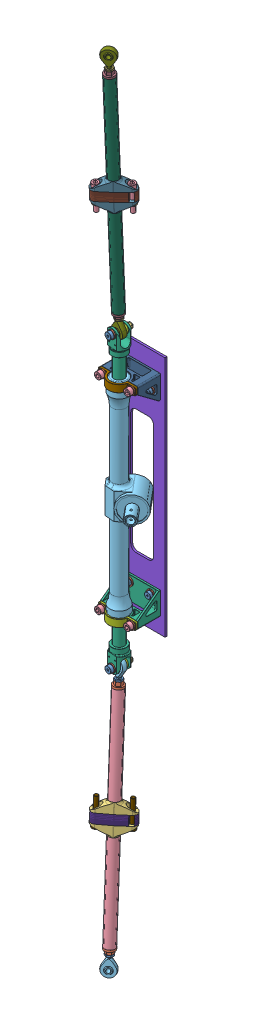
SolidWorks assembly PUTM-S-SS-SS-Assembly, configuration Domyślna. Lengths in mm.
Overall size (90.19 1233 99.62).
97 component instances, 26 part files, 74 mates.
Components (placement in the parent):
- PUTM-FT-ELESA_ISO7379-1: PUTM-FT-ELESA_ISO7379 [5-M4-8] at (-111.5 134.925 123.1137) x (0 0 1) z (0.610354 -0.792129 0) size (20 9 9)
- PUTM-FT-ELESA_ISO7379-2: PUTM-FT-ELESA_ISO7379 [5-M4-8] at (-78.5 134.925 123.1137) x (0 0 1) z (0.983488 -0.180971 0) size (20 9 9)
- PUTM-FT-ELESA_ISO7379-3: PUTM-FT-ELESA_ISO7379 [5-M4-8] at (-78.5 -134.925 123.1137) x (0 0 1) z (0.645637 -0.763644 0) size (20 9 9)
- PUTM-FT-ELESA_ISO7379-4: PUTM-FT-ELESA_ISO7379 [5-M4-8] at (-111.5 -134.925 123.1137) x (0 0 1) z (0.973518 0.228612 0) size (20 9 9)
- PUTM-FT-FABORY_ISO7089-1: PUTM-FT-FABORY_ISO7089 [M6 [38093.060.001]] at (-78.5 134.925 117.5137) size (12 12 1.6)
- PUTM-FT-FABORY_ISO7089-2: PUTM-FT-FABORY_ISO7089 [M6 [38093.060.001]] at (-111.5 134.925 117.5137) x (0.981941 0.189188 0) z (0 0 1) size (12 12 1.6)
- PUTM-FT-FABORY_ISO7089-3: PUTM-FT-FABORY_ISO7089 [M6 [38093.060.001]] at (-78.5 134.925 109.9) x (0.998363 0.05719 0) z (0 0 1) size (12 12 1.6)
- PUTM-FT-FABORY_ISO7089-4: PUTM-FT-FABORY_ISO7089 [M6 [38093.060.001]] at (-111.5 134.925 109.9) size (12 12 1.6)
- PUTM-FT-FABORY_DIN985-1: PUTM-FT-FABORY_DIN985 [M4 [12348.040.001]] at (-78.5 134.925 109.9) x (0.84714 0.53137 0) z (0 0 -1) size (8.48 7.4 5.2)
- PUTM-FT-FABORY_DIN985-2: PUTM-FT-FABORY_DIN985 [M4 [12348.040.001]] at (-111.5 134.925 109.9) x (-0.951211 0.308542 0) z (0 0 -1) size (8.48 7.4 5.2)
- PUTM-FT-FABORY_ISO7089-5: PUTM-FT-FABORY_ISO7089 [M6 [38093.060.001]] at (-111.5 -134.925 117.5137) x (0.854895 0.518802 0) z (0 0 1) size (12 12 1.6)
- PUTM-FT-FABORY_ISO7089-6: PUTM-FT-FABORY_ISO7089 [M6 [38093.060.001]] at (-78.5 -134.925 119.1137) x (-0.744163 -0.667998 0) z (0 0 -1) size (12 12 1.6)
- PUTM-FT-FABORY_ISO7089-7: PUTM-FT-FABORY_ISO7089 [M6 [38093.060.001]] at (-78.5 -134.925 109.9) x (0.999093 0.042591 0) z (0 0 1) size (12 12 1.6)
- PUTM-FT-FABORY_ISO7089-8: PUTM-FT-FABORY_ISO7089 [M6 [38093.060.001]] at (-111.5 -134.925 109.9) x (0.99977 0.021461 0) z (0 0 1) size (12 12 1.6)
- PUTM-FT-FABORY_DIN985-3: PUTM-FT-FABORY_DIN985 [M4 [12348.040.001]] at (-111.5 -134.925 109.9) x (-0.966924 0.255063 0) z (0 0 -1) size (8.48 7.4 5.2)
- PUTM-FT-FABORY_DIN985-4: PUTM-FT-FABORY_DIN985 [M4 [12348.040.001]] at (-78.5 -134.925 109.9) x (-0.223802 0.974635 0) z (0 0 -1) size (8.48 7.4 5.2)
- PUTM-FT-FABORY_ISO7089-9: PUTM-FT-FABORY_ISO7089 [M6 [38093.060.001]] at (-72.77 155.375 153.0074) size (12 12 1.6)
- PUTM-FT-FABORY_ISO7089-10: PUTM-FT-FABORY_ISO7089 [M6 [38093.060.001]] at (-117.23 155.375 153.0074) size (12 12 1.6)
- PUTM-FT-FABORY_ISO912-2: PUTM-FT-FABORY_ISO912 [M6x35 [07071.060.035]] at (-72.77 155.375 160.6074) x (0 0 1) z (-0.742041 -0.670355 0) size (41 10 10)
- PUTM-FT-FABORY_ISO912-3: PUTM-FT-FABORY_ISO912 [M6x35 [07071.060.035]] at (-117.23 155.375 160.6074) x (0 0 1) z (-0.923728 -0.383049 0) size (41 10 10)
- PUTM-FT-FABORY_ISO7089-11: PUTM-FT-FABORY_ISO7089 [M6 [38093.060.001]] at (-117.5102 -155.9569 153.0074) x (0.995286 0.096987 0) z (0 0 1) size (12 12 1.6)
- PUTM-FT-FABORY_ISO7089-12: PUTM-FT-FABORY_ISO7089 [M6 [38093.060.001]] at (-72.7949 -155.7273 153.0074) x (0.981722 0.190319 0) z (0 0 1) size (12 12 1.6)
- PUTM-FT-FABORY_ISO912-4: PUTM-FT-FABORY_ISO912 [M6x35 [07071.060.035]] at (-117.23 -155.375 160.6074) x (0 0 1) z (-0.988029 -0.154267 0) size (41 10 10)
- PUTM-FT-FABORY_ISO912-5: PUTM-FT-FABORY_ISO912 [M6x35 [07071.060.035]] at (-72.77 -155.375 160.6074) x (0 0 1) z (-0.923728 -0.383049 0) size (41 10 10)
- PUTM-FT-ELESA_ISO7379-8: PUTM-FT-ELESA_ISO7379 [6-M5-20] at (-96.3797 -220.88 165.7444) x (-0.085748 0 0.996317) z (-0.066283 0.997785 -0.005705) size (34 10 10)
- PUTM-FT-ELESA_ISO7379-9: PUTM-FT-ELESA_ISO7379 [6-M5-20] at (-96.3797 221.1 165.7444) x (-0.085748 0 0.996317) z (0.272109 0.961981 0.023419) size (34 10 10)
- PUTM-FT-FABORY_ISO7089-13: PUTM-FT-FABORY_ISO7089 [M6 [38093.060.001]] at (-95.8566 -220.88 159.6669) x (0.991444 0.098779 0.085329) z (-0.085748 0 0.996317) size (12 12 1.6)
- PUTM-FT-FABORY_ISO7089-14: PUTM-FT-FABORY_ISO7089 [M6 [38093.060.001]] at (-94.0062 221.1 138.1664) x (0.994622 0.058297 0.085602) z (-0.085748 0 0.996317) size (12 12 1.6)
- PUTM-FT-FABORY_ISO7089-15: PUTM-FT-FABORY_ISO7089 [M6 [38093.060.001]] at (-95.8566 221.1 159.6669) x (0.996317 0 0.085748) z (-0.085748 0 0.996317) size (12 12 1.6)
- PUTM-FT-FABORY_ISO7089-16: PUTM-FT-FABORY_ISO7089 [M6 [38093.060.001]] at (-94.0062 -220.88 138.1664) x (0.996302 -0.005391 0.085747) z (-0.085748 0 0.996317) size (12 12 1.6)
- PUTM-FT-FABORY_DIN985-5: PUTM-FT-FABORY_DIN985 [M5 [12348.050.001]] at (-94.0062 -220.88 138.1664) x (-0.902072 -0.424544 -0.077637) z (0.085748 0 -0.996317) size (9.51 8.27 5.13)
- PUTM-FT-FABORY_DIN985-6: PUTM-FT-FABORY_DIN985 [M5 [12348.050.001]] at (-94.0062 221.1 138.1664) x (-0.834822 -0.545812 -0.071849) z (0.085748 0 -0.996317) size (9.51 8.27 5.13)
- PUTM-S-SS-SS-Kinematics-1: PUTM-S-SS-SS-Kinematics [Domyślna] x (0 0 -1) z (-1 0 0)
- PUTM-S-SS-SS-Rack_and_pinion-1: PUTM-S-SS-SS-Rack_and_pinion [Domyślna] at (-74.032 -13.3697 144.0858) x (0 -1 0) z (0.767613 0 -0.640914) size (459.34 60.02 52.94)
  - PUTM-S-SS-SS-Pinion-1: PUTM-S-SS-SS-Pinion [Domyślna] at (-13.4847 -7.9013 -9.0673) size (322.08 60.02 50.73)
  - PUTM-S-SS-SS-Rack-1: PUTM-S-SS-SS-Rack [Domyślna] at (-13.4797 9.1187 -19.7023) x (0 -0.704375 0.709828) z (0 0.709828 0.704375) size (25.4 457.21 22.5)
  - PUTM-S-SS-SS-Mush-1: PUTM-S-SS-SS-Mush [Domyślna] at (207.5103 5.9244 -22.872) x (-0.966337 -0.181222 0.182625) z (0.257281 -0.680663 0.685933) size (14.19 5.5 14.19)
  - PUTM-S-SS-SS-Mush-2: PUTM-S-SS-SS-Mush [Domyślna] at (207.5103 12.3129 -16.5326) x (-0.966337 -0.181222 0.182625) z (-0.257281 0.680663 -0.685933) size (14.19 5.5 14.19)
  - PUTM-S-SS-SS-Mush-3: PUTM-S-SS-SS-Mush [Domyślna] at (-234.4697 5.9244 -22.872) x (0.966337 -0.181222 0.182625) z (0.257281 0.680663 -0.685933) size (14.19 5.5 14.19)
  - PUTM-S-SS-SS-Mush-4: PUTM-S-SS-SS-Mush [Domyślna] at (-234.4697 12.3129 -16.5326) x (0.966337 -0.181222 0.182625) z (-0.257281 -0.680663 0.685933) size (14.19 5.5 14.19)
- PUTM-S-SS-SS-Rack_mounting_plate-1: PUTM-S-SS-SS-Rack_mounting_plate [Domyślna] at origin size (70 370 3)
- PUTM-S-SS-SS-Upper_rack_mount-1: PUTM-S-SS-SS-Upper_rack_mount [Domyślna] at (-95 149.815 149.7137) x (-1 0 0) z (0 0 -1) size (57.15 11.11 15.77)
- PUTM-S-SS-SS-Lower_rack_mount-1: PUTM-S-SS-SS-Lower_rack_mount [Domyślna] at (-95 149.925 149.7137) x (-1 0 0) z (0 0 -1) size (57 35.07 35.2)
- PUTM-S-SS-SS-TRS-Assembly-1: PUTM-S-SS-SS-TRS-Assembly [Domyślna] at (-84.7573 579.916 174.534) x (-0.028456 -0.997192 -0.069271) z (0.623082 -0.071884 0.778846) size (405.25 54.72 22.34)
  - PUTM-S-Shims-5: PUTM-S-Shims [1mm] at (163.6234 0 0) x (0 0.999297 -0.0375) z (-1 0 0) size (53.32 15.5 1)
  - PUTM-S-Shims-6: PUTM-S-Shims [1mm] at (164.6234 0 0) x (0 0.999297 -0.0375) z (-1 0 0) size (53.32 15.5 1)
  - PUTM-S-Shims-7: PUTM-S-Shims [1mm] at (165.6234 0 0) x (0 0.999297 -0.0375) z (-1 0 0) size (53.32 15.5 1)
  - PUTM-S-Shims-8: PUTM-S-Shims [1mm] at (166.6234 0 0) x (0 0.999297 -0.0375) z (-1 0 0) size (53.32 15.5 1)
  - PUTM-S-Shims-9: PUTM-S-Shims [2mm] at (168.6234 0 0) x (0 0.999297 -0.0375) z (-1 0 0) size (53.32 15.5 2)
  - PUTM-S-Shims-10: PUTM-S-Shims [2mm] at (170.6234 0 0) x (0 0.999297 -0.0375) z (-1 0 0) size (53.32 15.5 2)
  - PUTM-S-Shims-11: PUTM-S-Shims [2mm] at (172.6234 0 0) x (0 0.999297 -0.0375) z (-1 0 0) size (53.32 15.5 2)
  - PUTM-S-Shims-12: PUTM-S-Shims [2mm] at (174.6234 0 0) x (0 0.999297 -0.0375) z (-1 0 0) size (53.32 15.5 2)
  - PUTM-S-Shims-1: PUTM-S-Shims [0,5mm] at (162.1234 0 0) x (0 0.999297 -0.0375) z (-1 0 0) size (53.32 15.5 0.5)
  - PUTM-S-Shims-2: PUTM-S-Shims [0,5mm] at (162.6234 0 0) x (0 0.999297 -0.0375) z (-1 0 0) size (53.32 15.5 0.5)
  - PUTM-S-Shims-3: PUTM-S-Shims [0,5mm] at (161.1234 0 0) x (0 0.999297 -0.0375) z (-1 0 0) size (53.32 15.5 0.5)
  - PUTM-S-Shims-4: PUTM-S-Shims [0,5mm] at (161.6234 0 0) x (0 0.999297 -0.0375) z (-1 0 0) size (53.32 15.5 0.5)
  - PUTM-FT-FABORY_ISO912-2: PUTM-FT-FABORY_ISO912 [M6x35 [07071.060.035]] at (152.6234 -19.9859 0.75) x (-1 0 0) z (0 0.003221 0.999995) size (41 10 10)
  - PUTM-FT-FABORY_ISO912-3: PUTM-FT-FABORY_ISO912 [M6x35 [07071.060.035]] at (152.6234 19.9859 -0.75) x (-1 0 0) z (0 0.003221 0.999995) size (41 10 10)
  - PUTM-FT-FABORY_DIN985-2: PUTM-FT-FABORY_DIN985 [M6 [12348.060.001]] at (176.6234 -19.9859 0.75) x (0 -0.467172 0.884166) z (1 0 0) size (11.9 10.35 6.18)
  - PUTM-FT-FABORY_DIN985-3: PUTM-FT-FABORY_DIN985 [M6 [12348.060.001]] at (176.6234 19.9859 -0.75) x (0 -0.467172 0.884166) z (1 0 0) size (11.9 10.35 6.18)
  - PUTM-FT-FABORY_ISO4035-2: PUTM-FT-FABORY_ISO4035 [M6 [11360.060.001]] at (-5.3 0 0) x (0 -0.995917 -0.09027) z (-1 0 0) size (11.55 10 2.7)
  - PUTM-FT-FABORY_ISO4035-3: PUTM-FT-FABORY_ISO4035 [M6 [11360.060.001]] at (343.2468 0 0) x (0 -0.999984 -0.005726) z (-1 0 0) size (11.55 10 2.7)
  - PUTM-S-SS-SS-Insert-1: PUTM-S-SS-SS-Insert [M6] at origin size (38.3 15.5 15.5)
  - PUTM-S-SS-SS-Insert-2: PUTM-S-SS-SS-Insert [M6] at (335.2468 0 0) x (-1 0 0) z (0 -0.005726 0.999984) size (38.3 15.5 15.5)
  - PUTM-S-SS-SS-Insert_shims_2-1: PUTM-S-SS-SS-Insert_shims_2 [Domyślna] at (160.6234 0 0) x (0 0.999297 -0.0375) z (0 0.0375 0.999297) size (54 55.42 20.32)
  - PUTM-S-SS-SS-Insert_shims_2-2: PUTM-S-SS-SS-Insert_shims_2 [Domyślna] at (174.6234 0 0) x (0 0.999297 -0.0375) z (0 -0.0375 -0.999297) size (54 55.42 20.32)
  - PUTM-S-SS-SS-Tie_rod-4: PUTM-S-SS-SS-Tie_rod [Domyślna] at (190.0468 0 0) x (0 0.999143 0.041392) z (1 0 0) size (15.5 15.5 142.2)
  - PUTM-S-SS-SS-Tie_rod-5: PUTM-S-SS-SS-Tie_rod [Domyślna] at (145.2 0 0) x (0 0.495709 0.868489) z (-1 0 0) size (15.5 15.5 142.2)
  - PUTM-S-rodend-1: PUTM-S-rodend [6mm] at (323.9475 0 0) x (0 0.689637 -0.724156) z (0 -0.724156 -0.689637) size (9 46 20)
  - PUTM-S-rodend-2: PUTM-S-rodend [6mm] at (10.6961 0 0) x (-0.000112 -0.061627 0.998099) z (0 -0.998099 -0.061627) size (9 46 20)
- LustroPUTM-S-SS-SS-TRS-Assembly-3: LustroPUTM-S-SS-SS-TRS-Assembly [Domyślna] at (-84.7573 -579.916 174.534) x (-0.028456 0.997192 -0.069271) z (-0.623082 -0.071884 -0.778846) size (405.25 54.72 22.34)
  - LustroPUTM-S-Shims-1: LustroPUTM-S-Shims [1mm] at (163.6234 0 0) x (0 0.999297 0.0375) z (1 0 0) size (53.32 15.5 1)
  - LustroPUTM-S-Shims-2: LustroPUTM-S-Shims [1mm] at (164.6234 0 0) x (0 0.999297 0.0375) z (1 0 0) size (53.32 15.5 1)
  - LustroPUTM-S-Shims-3: LustroPUTM-S-Shims [1mm] at (165.6234 0 0) x (0 0.999297 0.0375) z (1 0 0) size (53.32 15.5 1)
  - LustroPUTM-S-Shims-4: LustroPUTM-S-Shims [1mm] at (166.6234 0 0) x (0 0.999297 0.0375) z (1 0 0) size (53.32 15.5 1)
  - LustroPUTM-S-Shims-5: LustroPUTM-S-Shims [2mm] at (168.6234 0 0) x (0 0.999297 0.0375) z (1 0 0) size (53.32 15.5 2)
  - LustroPUTM-S-Shims-6: LustroPUTM-S-Shims [2mm] at (170.6234 0 0) x (0 0.999297 0.0375) z (1 0 0) size (53.32 15.5 2)
  - LustroPUTM-S-Shims-7: LustroPUTM-S-Shims [2mm] at (172.6234 0 0) x (0 0.999297 0.0375) z (1 0 0) size (53.32 15.5 2)
  - LustroPUTM-S-Shims-8: LustroPUTM-S-Shims [2mm] at (174.6234 0 0) x (0 0.999297 0.0375) z (1 0 0) size (53.32 15.5 2)
  - LustroPUTM-S-Shims-9: LustroPUTM-S-Shims [0,5mm] at (162.1234 0 0) x (0 0.999297 0.0375) z (1 0 0) size (53.32 15.5 0.5)
  - LustroPUTM-S-Shims-10: LustroPUTM-S-Shims [0,5mm] at (162.6234 0 0) x (0 0.999297 0.0375) z (1 0 0) size (53.32 15.5 0.5)
  - LustroPUTM-S-Shims-11: LustroPUTM-S-Shims [0,5mm] at (161.1234 0 0) x (0 0.999297 0.0375) z (1 0 0) size (53.32 15.5 0.5)
  - LustroPUTM-S-Shims-12: LustroPUTM-S-Shims [0,5mm] at (161.6234 0 0) x (0 0.999297 0.0375) z (1 0 0) size (53.32 15.5 0.5)
  - LustroPUTM-FT-FABORY_ISO912-1: LustroPUTM-FT-FABORY_ISO912 [M6x35 [07071.060.035]] at (152.6234 -19.9859 -0.75) x (-1 0 0) z (0 -0.003221 0.999995) size (41 10 10)
  - LustroPUTM-FT-FABORY_ISO912-2: LustroPUTM-FT-FABORY_ISO912 [M6x35 [07071.060.035]] at (152.6234 19.9859 0.75) x (-1 0 0) z (0 -0.003221 0.999995) size (41 10 10)
  - LustroPUTM-FT-FABORY_ISO4035-1: LustroPUTM-FT-FABORY_ISO4035 [M6 [11360.060.001]] at (-5.3 0 0) x (0 -0.995917 0.09027) z (1 0 0) size (11.55 10 2.7)
  - LustroPUTM-FT-FABORY_ISO4035-2: LustroPUTM-FT-FABORY_ISO4035 [M6 [11360.060.001]] at (343.2468 0 0) x (0 -0.999984 0.005726) z (1 0 0) size (11.55 10 2.7)
  - LustroPUTM-S-SS-SS-Insert-1: LustroPUTM-S-SS-SS-Insert [M6] at origin size (38.3 15.5 15.5)
  - LustroPUTM-S-SS-SS-Insert-2: LustroPUTM-S-SS-SS-Insert [M6] at (335.2468 0 0) x (-1 0 0) z (0 0.005726 0.999984) size (38.3 15.5 15.5)
  - LustroPUTM-S-SS-SS-Insert_shims_2-1: LustroPUTM-S-SS-SS-Insert_shims_2 [Domyślna] at (160.6234 0 0) x (0 0.999297 0.0375) z (0 -0.0375 0.999297) size (54 55.42 20.32)
  - LustroPUTM-S-SS-SS-Insert_shims_2-2: LustroPUTM-S-SS-SS-Insert_shims_2 [Domyślna] at (174.6234 0 0) x (0 0.999297 0.0375) z (0 0.0375 -0.999297) size (54 55.42 20.32)
  - LustroPUTM-S-SS-SS-Tie_rod-1: LustroPUTM-S-SS-SS-Tie_rod [Domyślna] at (190.0468 0 0) x (0 0.999143 -0.041392) z (-1 0 0) size (15.5 15.5 142.2)
  - LustroPUTM-S-SS-SS-Tie_rod-2: LustroPUTM-S-SS-SS-Tie_rod [Domyślna] at (145.2 0 0) x (0 0.495709 -0.868489) z (1 0 0) size (15.5 15.5 142.2)
  - LustroPUTM-S-rodend-1: LustroPUTM-S-rodend [6mm] at (323.9475 0 0) x (0 0.689637 0.724156) z (0 0.724156 -0.689637) size (9 46 20)
  - LustroPUTM-S-rodend-2: LustroPUTM-S-rodend [6mm] at (10.6961 0 0) x (-0.000112 -0.061627 -0.998099) z (0 0.998099 -0.061627) size (9 46 20)
- LustroPUTM-S-SS-SS-Lower_rack_mount-2: LustroPUTM-S-SS-SS-Lower_rack_mount [Domyślna] at (-95 -149.925 149.7137) x (-1 0 0) z (0 0 1) size (57 35.07 35.2)
- LustroPUTM-S-SS-SS-Upper_rack_mount-2: LustroPUTM-S-SS-SS-Upper_rack_mount [Domyślna] at (-95 -149.815 149.7137) x (-1 0 0) z (0 0 1) size (57.15 11.11 15.77)
Mates (geometry in assembly coordinates):
- Wspólnie20: coincident anti-aligned: plane of PUTM-FT-ELESA_ISO7379-2 through (-79.3144 130.4993 119.1137) normal (0 0 -1); plane of PUTM-FT-FABORY_ISO7089-1 through (-78.5 134.925 119.1137) normal (0 0 1)
- Koncentryczne8: concentric aligned: cylinder of PUTM-FT-ELESA_ISO7379-2 through (-78.5 134.925 123.1137) axis (0 0 -1) radius 2; cylinder of PUTM-FT-FABORY_ISO7089-3 through (-78.5 134.925 111.5) axis (0 0 -1) radius 3.2
- Wspólnie21: coincident anti-aligned: plane of PUTM-S-SS-SS-Rack_mounting_plate-1 through (0 0 111.5) normal (0 0 -1); plane of PUTM-FT-FABORY_ISO7089-3 through (-78.5 134.925 111.5) normal (0 0 1)
- Koncentryczne9: concentric aligned: circle of PUTM-FT-ELESA_ISO7379-2; circle of PUTM-FT-FABORY_DIN985-1
- Wspólnie25: coincident anti-aligned: plane of PUTM-FT-FABORY_ISO7089-3 through (-78.5 134.925 109.9) normal (0 0 -1); plane of PUTM-FT-FABORY_DIN985-1 through (-78.5 134.925 109.9) normal (0 0 1)
- Wspólnie27: coincident anti-aligned: plane of PUTM-S-SS-SS-Rack_mounting_plate-1 through (0 0 111.5) normal (0 0 -1); plane of PUTM-FT-FABORY_ISO7089-4 through (-111.5 134.925 111.5) normal (0 0 1)
- Koncentryczne11: concentric aligned: cylinder of PUTM-FT-FABORY_ISO7089-2 through (-111.5 134.925 119.1137) axis (0 0 -1) radius 3.2; cylinder of PUTM-FT-FABORY_ISO7089-4 through (-111.5 134.925 111.5) axis (0 0 -1) radius 3.2
- Koncentryczne12: concentric aligned: cylinder of PUTM-FT-ELESA_ISO7379-1 through (-111.5 134.925 123.1137) axis (0 0 -1) radius 2.5; cylinder of PUTM-FT-FABORY_ISO7089-2 through (-111.5 134.925 119.1137) axis (0 0 -1) radius 3.2
- Wspólnie28: coincident anti-aligned: plane of PUTM-FT-ELESA_ISO7379-1 through (-115.0646 132.1784 119.1137) normal (0 0 -1); plane of PUTM-FT-FABORY_ISO7089-2 through (-111.5 134.925 119.1137) normal (0 0 1)
- Koncentryczne13: concentric anti-aligned: cylinder of PUTM-FT-ELESA_ISO7379-1 through (-111.5 134.925 123.1137) axis (0 0 -1) radius 2; cylinder of PUTM-FT-FABORY_DIN985-2 through (-111.5 134.925 107) axis (0 0 1) radius 2
- Wspólnie29: coincident anti-aligned: plane of PUTM-FT-FABORY_ISO7089-4 through (-111.5 134.925 109.9) normal (0 0 -1); plane of PUTM-FT-FABORY_DIN985-2 through (-111.5 134.925 109.9) normal (0 0 1)
- Koncentryczne16: concentric anti-aligned: cylinder of PUTM-FT-FABORY_ISO7089-6 through (-78.5 -134.925 117.5137) axis (0 0 1) radius 3.2; cylinder of PUTM-FT-FABORY_ISO7089-7 through (-78.5 -134.925 111.5) axis (0 0 -1) radius 3.2
- Koncentryczne17: concentric aligned: cylinder of PUTM-FT-FABORY_ISO7089-5 through (-111.5 -134.925 119.1137) axis (0 0 -1) radius 6; cylinder of PUTM-FT-FABORY_ISO7089-8 through (-111.5 -134.925 111.5) axis (0 0 -1) radius 6
- Wspólnie30: coincident anti-aligned: plane of PUTM-S-SS-SS-Rack_mounting_plate-1 through (0 0 111.5) normal (0 0 -1); plane of PUTM-FT-FABORY_ISO7089-7 through (-78.5 -134.925 111.5) normal (0 0 1)
- Wspólnie31: coincident anti-aligned: plane of PUTM-S-SS-SS-Rack_mounting_plate-1 through (0 0 111.5) normal (0 0 -1); plane of PUTM-FT-FABORY_ISO7089-8 through (-111.5 -134.925 111.5) normal (0 0 1)
- Koncentryczne18: concentric anti-aligned: cylinder of PUTM-FT-ELESA_ISO7379-3 through (-78.5 -134.925 123.1137) axis (0 0 -1) radius 2.5; cylinder of PUTM-FT-FABORY_ISO7089-6 through (-78.5 -134.925 117.5137) axis (0 0 1) radius 3.2
- Koncentryczne19: concentric aligned: cylinder of PUTM-FT-ELESA_ISO7379-4 through (-111.5 -134.925 123.1137) axis (0 0 -1) radius 2.5; cylinder of PUTM-FT-FABORY_ISO7089-5 through (-111.5 -134.925 119.1137) axis (0 0 -1) radius 3.2
- Wspólnie34: coincident anti-aligned: plane of PUTM-FT-ELESA_ISO7379-4 through (-110.4712 -139.3058 119.1137) normal (0 0 -1); plane of PUTM-FT-FABORY_ISO7089-5 through (-111.5 -134.925 119.1137) normal (0 0 1)
- Wspólnie35: coincident anti-aligned: plane of PUTM-FT-ELESA_ISO7379-3 through (-81.9364 -137.8304 119.1137) normal (0 0 -1); plane of PUTM-FT-FABORY_ISO7089-6 through (-78.5 -134.925 119.1137) normal (0 0 1)
- Koncentryczne20: concentric aligned: cylinder of PUTM-FT-ELESA_ISO7379-3 through (-78.5 -134.925 123.1137) axis (0 0 -1) radius 2; cone of PUTM-FT-FABORY_DIN985-4 through (-78.5 -134.925 109.9) axis (0 0 -1)
- Koncentryczne21: concentric aligned: cylinder of PUTM-FT-ELESA_ISO7379-4 through (-111.5 -134.925 123.1137) axis (0 0 -1) radius 2; cone of PUTM-FT-FABORY_DIN985-3 through (-111.5 -134.925 109.9) axis (0 0 -1)
- Wspólnie36: coincident anti-aligned: plane of PUTM-FT-FABORY_ISO7089-8 through (-111.5 -134.925 109.9) normal (0 0 -1); plane of PUTM-FT-FABORY_DIN985-3 through (-111.5 -134.925 109.9) normal (0 0 1)
- Wspólnie37: coincident anti-aligned: plane of PUTM-FT-FABORY_ISO7089-7 through (-78.5 -134.925 109.9) normal (0 0 -1); plane of PUTM-FT-FABORY_DIN985-4 through (-78.5 -134.925 109.9) normal (0 0 1)
- Koncentryczne24: concentric aligned: cylinder of PUTM-FT-FABORY_ISO7089-9 through (-72.77 155.375 154.6074) axis (0 0 -1) radius 3.2; cylinder of PUTM-FT-FABORY_ISO912-2 through (-72.77 155.375 37.4484) axis (0 0 -1) radius 3
- Wspólnie40: coincident anti-aligned: plane of PUTM-FT-FABORY_ISO7089-9 through (-72.77 155.375 154.6074) normal (0 0 1); plane of PUTM-FT-FABORY_ISO912-2 through (-76.1218 159.0852 154.6074) normal (0 0 -1)
- Koncentryczne25: concentric aligned: cylinder of PUTM-FT-FABORY_ISO7089-10 through (-117.23 155.375 154.6074) axis (0 0 -1) radius 3.2; cylinder of PUTM-FT-FABORY_ISO912-3 through (-117.23 155.375 37.4484) axis (0 0 -1) radius 3
- Wspólnie41: coincident anti-aligned: plane of PUTM-FT-FABORY_ISO7089-10 through (-117.23 155.375 154.6074) normal (0 0 1); plane of PUTM-FT-FABORY_ISO912-3 through (-119.1452 159.9936 154.6074) normal (0 0 -1)
- Wspólnie44: coincident anti-aligned: plane of PUTM-FT-FABORY_ISO7089-12 through (-72.7949 -155.7273 154.6074) normal (0 0 1); plane of PUTM-FT-FABORY_ISO912-5 through (-74.6852 -150.7564 154.6074) normal (0 0 -1)
- Wspólnie45: coincident anti-aligned: plane of PUTM-FT-FABORY_ISO7089-11 through (-117.5102 -155.9569 154.6074) normal (0 0 1); plane of PUTM-FT-FABORY_ISO912-4 through (-118.0013 -150.4349 154.6074) normal (0 0 -1)
- Koncentryczne30: concentric aligned: cylinder of PUTM-S-SS-SS-Rack_and_pinion-1/PUTM-S-SS-SS-Rack-1 through (-94.1434 221.1 139.7605) axis (0.085748 0 -0.996317) radius 3.175; cylinder of PUTM-FT-FABORY_ISO7089-15 through (-95.9938 221.1 161.261) axis (0.085748 0 -0.996317) radius 3.2
- Koncentryczne31: concentric aligned: cylinder of PUTM-S-SS-SS-Rack_and_pinion-1/PUTM-S-SS-SS-Rack-1 through (-94.1434 221.1 139.7605) axis (0.085748 0 -0.996317) radius 3.175; cylinder of PUTM-FT-FABORY_ISO7089-14 through (-94.1434 221.1 139.7605) axis (0.085748 0 -0.996317) radius 3.2
- Wspólnie46: coincident anti-aligned: plane of PUTM-S-SS-SS-Rack_and_pinion-1/PUTM-S-SS-SS-Rack-1 through (-108.5098 228.715 158.5779) normal (-0.085748 0 0.996317); plane of PUTM-FT-FABORY_ISO7089-15 through (-95.8566 221.1 159.6669) normal (0.085748 0 -0.996317)
- Wspólnie47: coincident anti-aligned: plane of PUTM-S-SS-SS-Rack_and_pinion-1/PUTM-S-SS-SS-Rack-1 through (-106.7966 228.715 138.6715) normal (0.085748 0 -0.996317); plane of PUTM-FT-FABORY_ISO7089-14 through (-94.1434 221.1 139.7605) normal (-0.085748 0 0.996317)
- Koncentryczne32: concentric aligned: cylinder of PUTM-S-SS-SS-Rack_and_pinion-1/PUTM-S-SS-SS-Rack-1 through (-94.1434 221.1 139.7605) axis (0.085748 0 -0.996317) radius 3.175; cylinder of PUTM-FT-ELESA_ISO7379-9 through (-96.3797 221.1 165.7444) axis (0.085748 0 -0.996317) radius 3
- Wspólnie48: coincident anti-aligned: plane of PUTM-FT-ELESA_ISO7379-9 through (-91.2016 219.7344 161.6734) normal (0.085748 0 -0.996317); plane of PUTM-FT-FABORY_ISO7089-15 through (-95.9938 221.1 161.261) normal (-0.085748 0 0.996317)
- Koncentryczne33: concentric aligned: cylinder of PUTM-S-SS-SS-Rack_and_pinion-1/PUTM-S-SS-SS-Rack-1 through (-94.1434 -220.88 139.7605) axis (0.085748 0 -0.996317) radius 3.175; cylinder of PUTM-FT-FABORY_ISO7089-13 through (-95.9938 -220.88 161.261) axis (0.085748 0 -0.996317) radius 3.2
- Koncentryczne34: concentric aligned: cylinder of PUTM-S-SS-SS-Rack_and_pinion-1/PUTM-S-SS-SS-Rack-1 through (-94.1434 -220.88 139.7605) axis (0.085748 0 -0.996317) radius 3.175; cylinder of PUTM-FT-FABORY_ISO7089-16 through (-94.1434 -220.88 139.7605) axis (0.085748 0 -0.996317) radius 3.2
- Koncentryczne35: concentric aligned: cylinder of PUTM-S-SS-SS-Rack_and_pinion-1/PUTM-S-SS-SS-Rack-1 through (-94.1434 -220.88 139.7605) axis (0.085748 0 -0.996317) radius 3.175; cylinder of PUTM-FT-ELESA_ISO7379-8 through (-96.3797 -220.88 165.7444) axis (0.085748 0 -0.996317) radius 3
- Wspólnie50: coincident anti-aligned: plane of PUTM-S-SS-SS-Rack_and_pinion-1/PUTM-S-SS-SS-Rack-1 through (-108.5098 -228.495 158.5779) normal (-0.085748 0 0.996317); plane of PUTM-FT-FABORY_ISO7089-13 through (-95.8566 -220.88 159.6669) normal (0.085748 0 -0.996317)
- Wspólnie51: coincident anti-aligned: plane of PUTM-FT-ELESA_ISO7379-8 through (-91.0233 -220.5474 161.6888) normal (0.085748 0 -0.996317); plane of PUTM-FT-FABORY_ISO7089-13 through (-95.9938 -220.88 161.261) normal (-0.085748 0 0.996317)
- Wspólnie52: coincident anti-aligned: plane of PUTM-S-SS-SS-Rack_and_pinion-1/PUTM-S-SS-SS-Rack-1 through (-106.7966 -228.495 138.6715) normal (0.085748 0 -0.996317); plane of PUTM-FT-FABORY_ISO7089-16 through (-94.1434 -220.88 139.7605) normal (-0.085748 0 0.996317)
- Koncentryczne36: concentric anti-aligned: cylinder of PUTM-FT-ELESA_ISO7379-8 through (-96.3797 -220.88 165.7444) axis (0.085748 0 -0.996317) radius 2.5; cylinder of PUTM-FT-FABORY_DIN985-5 through (-93.7318 -220.88 134.9782) axis (-0.085748 0 0.996317) radius 2.5
- Koncentryczne37: concentric anti-aligned: cylinder of PUTM-FT-ELESA_ISO7379-9 through (-96.3797 221.1 165.7444) axis (0.085748 0 -0.996317) radius 2.5; cylinder of PUTM-FT-FABORY_DIN985-6 through (-93.7318 221.1 134.9782) axis (-0.085748 0 0.996317) radius 2.5
- Wspólnie60: coincident anti-aligned: plane of PUTM-FT-FABORY_ISO7089-16 through (-94.0062 -220.88 138.1664) normal (0.085748 0 -0.996317); plane of PUTM-FT-FABORY_DIN985-5 through (-94.0062 -220.88 138.1664) normal (-0.085748 0 0.996317)
- Wspólnie61: coincident anti-aligned: plane of PUTM-FT-FABORY_ISO7089-14 through (-94.0062 221.1 138.1664) normal (0.085748 0 -0.996317); plane of PUTM-FT-FABORY_DIN985-6 through (-94.0062 221.1 138.1664) normal (-0.085748 0 0.996317)
- Koncentryczne38: concentric anti-aligned: line of PUTM-S-SS-SS-Kinematics-1 through (-95 220.98 149.6) axis (0.028456 0.997192 0.069271); cylinder of PUTM-S-SS-SS-TRS-Assembly-1/PUTM-S-SS-SS-Tie_rod-5 through (-84.8427 576.9245 174.3262) axis (-0.028456 -0.997192 -0.069271) radius 7.75
- Wspólnie65: coincident: point of PUTM-S-SS-SS-Kinematics-1; point of PUTM-S-SS-SS-TRS-Assembly-1/PUTM-S-rodend-1
- Prostopadle1: perpendicular: plane of PUTM-S-SS-SS-Rack_and_pinion-1/PUTM-S-SS-SS-Rack-1 through (-108.2659 0.11 155.7434) normal (0.085748 0 -0.996317); plane of PUTM-S-SS-SS-TRS-Assembly-1/PUTM-S-rodend-1 through (-93.9756 256.8782 152.0937) normal (-0.995728 0.034368 -0.085698)
- Koncentryczne41: concentric anti-aligned: cylinder of PUTM-S-SS-SS-Lower_rack_mount-1 through (-78.5 134.925 117.5137) axis (0 0 1) radius 2.5; cylinder of PUTM-FT-ELESA_ISO7379-2 through (-78.5 134.925 123.1137) axis (0 0 -1) radius 2.5
- Wspólnie66: coincident anti-aligned: plane of PUTM-S-SS-SS-Lower_rack_mount-1 through (-95 149.925 117.5137) normal (0 0 1); plane of PUTM-FT-FABORY_ISO7089-1 through (-78.5 134.925 117.5137) normal (0 0 -1)
- Koncentryczne42: concentric aligned: circle of PUTM-S-SS-SS-Lower_rack_mount-1; circle of PUTM-FT-FABORY_ISO7089-1
- Koncentryczne43: concentric anti-aligned: cylinder of PUTM-S-SS-SS-Lower_rack_mount-1 through (-111.5 134.925 117.5137) axis (0 0 1) radius 2.5; cylinder of PUTM-FT-FABORY_ISO7089-2 through (-111.5 134.925 119.1137) axis (0 0 -1) radius 3.2
- Wspólnie67: coincident anti-aligned: plane of PUTM-S-SS-SS-Lower_rack_mount-1 through (-95 149.925 117.5137) normal (0 0 1); plane of PUTM-FT-FABORY_ISO7089-2 through (-111.5 134.925 117.5137) normal (0 0 -1)
- Równolegle14: parallel aligned: plane of PUTM-S-SS-SS-Rack_mounting_plate-1 through (0 0 114.5) normal (0 0 1); plane of PUTM-S-SS-SS-Upper_rack_mount-1 through (-66.425 160.925 153.0074) normal (0 0 1)
- Wspólnie69: coincident anti-aligned: plane of PUTM-S-SS-SS-Upper_rack_mount-1 through (-66.425 160.925 153.0074) normal (0 0 1); plane of PUTM-FT-FABORY_ISO7089-9 through (-72.77 155.375 153.0074) normal (0 0 -1)
- Koncentryczne45: concentric anti-aligned: cylinder of PUTM-S-SS-SS-Upper_rack_mount-1 through (-72.77 155.375 153.0074) axis (0 0 1) radius 3; cylinder of PUTM-FT-FABORY_ISO7089-9 through (-72.77 155.375 154.6074) axis (0 0 -1) radius 3.2
- Wspólnie70: coincident anti-aligned: plane of PUTM-S-SS-SS-Upper_rack_mount-1 through (-110.5347 160.925 153.0074) normal (0 0 1); plane of PUTM-FT-FABORY_ISO7089-10 through (-117.23 155.375 153.0074) normal (0 0 -1)
- Koncentryczne46: concentric anti-aligned: cylinder of PUTM-S-SS-SS-Upper_rack_mount-1 through (-117.23 155.375 153.0074) axis (0 0 1) radius 3; cylinder of PUTM-FT-FABORY_ISO7089-10 through (-117.23 155.375 154.6074) axis (0 0 -1) radius 3.2
- Wspólnie72: coincident anti-aligned: plane of PUTM-FT-FABORY_ISO7089-6 through (-78.5 -134.925 117.5137) normal (0 0 -1); plane of LustroPUTM-S-SS-SS-Lower_rack_mount-2 through (-95 -149.925 117.5137) normal (0 0 1)
- Koncentryczne49: concentric anti-aligned: cylinder of PUTM-FT-ELESA_ISO7379-3 through (-78.5 -134.925 123.1137) axis (0 0 -1) radius 2.5; cylinder of LustroPUTM-S-SS-SS-Lower_rack_mount-2 through (-78.5 -134.925 117.5137) axis (0 0 1) radius 2.5
- Wspólnie73: coincident anti-aligned: plane of PUTM-FT-FABORY_ISO7089-5 through (-111.5 -134.925 117.5137) normal (0 0 -1); plane of LustroPUTM-S-SS-SS-Lower_rack_mount-2 through (-95 -149.925 117.5137) normal (0 0 1)
- Koncentryczne50: concentric anti-aligned: cylinder of PUTM-FT-ELESA_ISO7379-4 through (-111.5 -134.925 123.1137) axis (0 0 -1) radius 2.5; cylinder of LustroPUTM-S-SS-SS-Lower_rack_mount-2 through (-111.5 -134.925 117.5137) axis (0 0 1) radius 2.5
- Koncentryczne55: concentric aligned: cylinder of PUTM-S-SS-SS-Rack_and_pinion-1/PUTM-S-SS-SS-Rack-1 through (-95 -192.675 149.7137) axis (0 1 0) radius 7.94; cylinder of LustroPUTM-S-SS-SS-Upper_rack_mount-2 through (-95 -160.925 149.7137) axis (0 1 0) radius 12.7
- Koncentryczne56: concentric aligned: cylinder of PUTM-S-SS-SS-Rack_and_pinion-1/PUTM-S-SS-SS-Pinion-1 through (-95 -160.925 149.7137) axis (0 1 0) radius 12.7; cylinder of LustroPUTM-S-SS-SS-Lower_rack_mount-2 through (-95 -160.926 149.7137) axis (0 1 0) radius 12.7
- Wspólnie80: coincident anti-aligned: plane of PUTM-S-SS-SS-Kinematics-1 through (0 0 0) normal (0 0 -1)
- Wspólnie81: coincident anti-aligned: plane of PUTM-S-SS-SS-Kinematics-1 through (0 0 0) normal (-1 0 0)
- Wspólnie82: coincident anti-aligned: plane of PUTM-S-SS-SS-Kinematics-1 through (0 0 0) normal (0 -1 0)
- Wspólnie83: coincident aligned: plane of PUTM-S-SS-SS-Rack_and_pinion-1/PUTM-S-SS-SS-Pinion-1 through (-95 -160.925 149.7137) normal (0 -1 0); plane of LustroPUTM-S-SS-SS-Upper_rack_mount-2 through (-95 -160.925 149.7137) normal (0 -1 0)
- Wspólnie84: coincident aligned: plane of LustroPUTM-S-SS-SS-Lower_rack_mount-2 through (-123.5 -160.925 114.5137) normal (0 -1 0); plane of LustroPUTM-S-SS-SS-Upper_rack_mount-2 through (-95 -160.925 149.7137) normal (0 -1 0)
- Równolegle15: parallel anti-aligned: line of PUTM-S-SS-SS-Kinematics-1 through (-95 0 149.6) axis (0.640914 0 0.767613); line of PUTM-S-SS-SS-Rack_and_pinion-1/PUTM-S-SS-SS-Pinion-1 through (-55.1589 0.115 172.4664) axis (-0.640914 0 -0.767613)
- Koncentryczne57: concentric anti-aligned: cylinder of PUTM-FT-FABORY_ISO912-4 through (-117.23 -155.375 37.4484) axis (0 0 -1) radius 3; cylinder of LustroPUTM-S-SS-SS-Upper_rack_mount-2 through (-117.23 -155.375 153.0074) axis (0 0 1) radius 3
- Koncentryczne58: concentric aligned: cylinder of PUTM-FT-FABORY_ISO912-5 through (-72.77 -155.375 37.4484) axis (0 0 -1) radius 3; circle of LustroPUTM-S-SS-SS-Upper_rack_mount-2
- Wspólnie87: coincident anti-aligned: plane of PUTM-FT-FABORY_ISO7089-11 through (-117.5102 -155.9569 153.0074) normal (0 0 -1); plane of LustroPUTM-S-SS-SS-Upper_rack_mount-2 through (-110.5347 -160.925 153.0074) normal (0 0 1)
- Wspólnie88: coincident anti-aligned: plane of PUTM-FT-FABORY_ISO7089-12 through (-72.7949 -155.7273 153.0074) normal (0 0 -1); plane of LustroPUTM-S-SS-SS-Upper_rack_mount-2 through (-66.425 -160.925 153.0074) normal (0 0 1)
